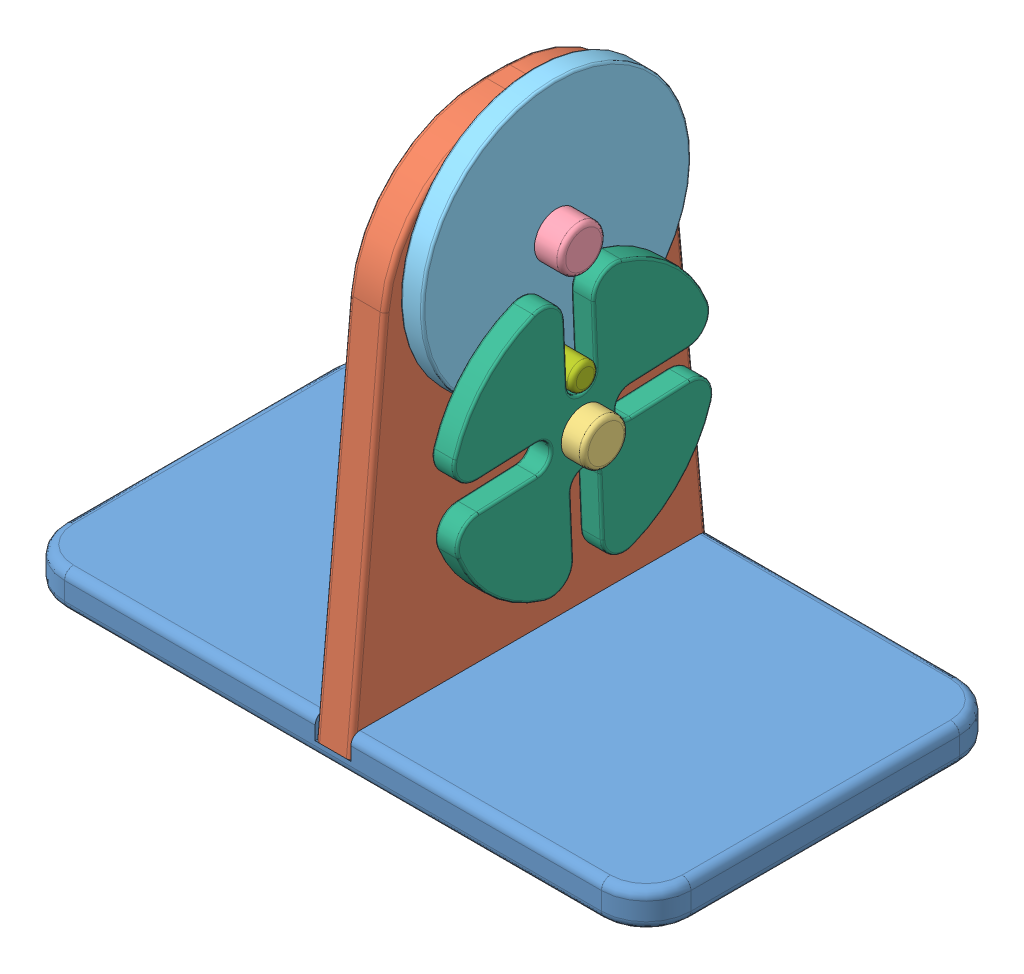
SolidWorks assembly Sestava1, configuration Default. Lengths in mm.
Overall size (140 118.78 80).
7 component instances, 7 part files, 13 mates.
Components (placement in the parent):
- Podstava-1: Podstava [Default] at origin size (140 8 80)
- Vzpera-1: Vzpera [Default] at (66 3 -40) size (8 110 80)
- VelkyCep2-3: VelkyCep2 [Default] at (66 53 -40) x (0 0.52449 -0.851417) z (-1 0 0) size (14 14 28)
- VelkyCep-1: VelkyCep [Default] at (66 88 -40) x (0 0.924225 0.381849) z (-1 0 0) size (14 14 23)
- Kotouc-1: Kotouc [Default] at (75 88 -40) x (1 0 0) z (0 0.026442 0.99965) size (5 60 60)
- MaltezskyKriz-1: MaltezskyKriz [Default] at (81 53 -40) x (0 -0.042791 0.999084) z (1 0 0) size (57.23 57.23 5)
- MalyCep-1: MalyCep [Default] at (75 64.0084 -39.3654) x (0 0.39446 0.918913) z (1 0 0) size (6 6 12)
Mates (geometry in assembly coordinates):
- Sjednocená5: coincident anti-aligned: plane of Podstava-1 through (66 3 -80.001) normal (0 1 0); plane of Vzpera-1 through (74 3 -80) normal (0 -1 0)
- Sjednocená6: coincident anti-aligned: line of Podstava-1 through (8 66 3) axis (0 1 0); line of Vzpera-1 through (6 73 3) axis (0 -1 0)
- Sjednocená7: coincident anti-aligned: plane of Podstava-1 through (74 8 -80.001) normal (-1 0 0); plane of Vzpera-1 through (74 3 -40) normal (1 0 0)
- Soustředná1: concentric aligned: cylinder of Vzpera-1 through (74 88 -40) axis (-1 0 0) radius 5; cylinder of VelkyCep-1 through (86 88 -40) axis (-1 0 0) radius 5
- Sjednocená8: coincident anti-aligned: plane of Vzpera-1 through (66 3 -40) normal (-1 0 0); plane of VelkyCep-1 through (66 88 -40) normal (1 0 0)
- Soustředná2: concentric aligned: cylinder of Vzpera-1 through (74 53 -40) axis (-1 0 0) radius 5; cylinder of VelkyCep2-3 through (91 53 -40) axis (-1 0 0) radius 5
- Sjednocená9: coincident aligned: plane of Vzpera-1 through (66 3 -40) normal (-1 0 0); circle of VelkyCep2-3
- Soustředná3: concentric aligned: cylinder of VelkyCep-1 through (86 88 -40) axis (-1 0 0) radius 5; cylinder of Kotouc-1 through (80 88 -40) axis (-1 0 0) radius 5
- Vzdálenost1: distance = 1 mm anti-aligned: plane of Kotouc-1 through (75 88 -40) normal (-1 0 0); plane of Vzpera-1 through (74 3 -40) normal (1 0 0)
- Soustředná4: concentric aligned: cylinder of Kotouc-1 through (80.001 64.0084 -39.3654) axis (-1 0 0) radius 3; cylinder of MalyCep-1 through (87 64.0084 -39.3654) axis (-1 0 0) radius 3
- Sjednocená14: coincident anti-aligned: circle of Kotouc-1; circle of MalyCep-1
- Soustředná6: concentric anti-aligned: cylinder of VelkyCep2-3 through (91 53 -40) axis (-1 0 0) radius 5; circle of MaltezskyKriz-1
- Vzdálenost4: distance = 1 mm anti-aligned: plane of Kotouc-1 through (80 88 -40) normal (1 0 0); plane of MaltezskyKriz-1 through (81 53 -40) normal (-1 0 0)
